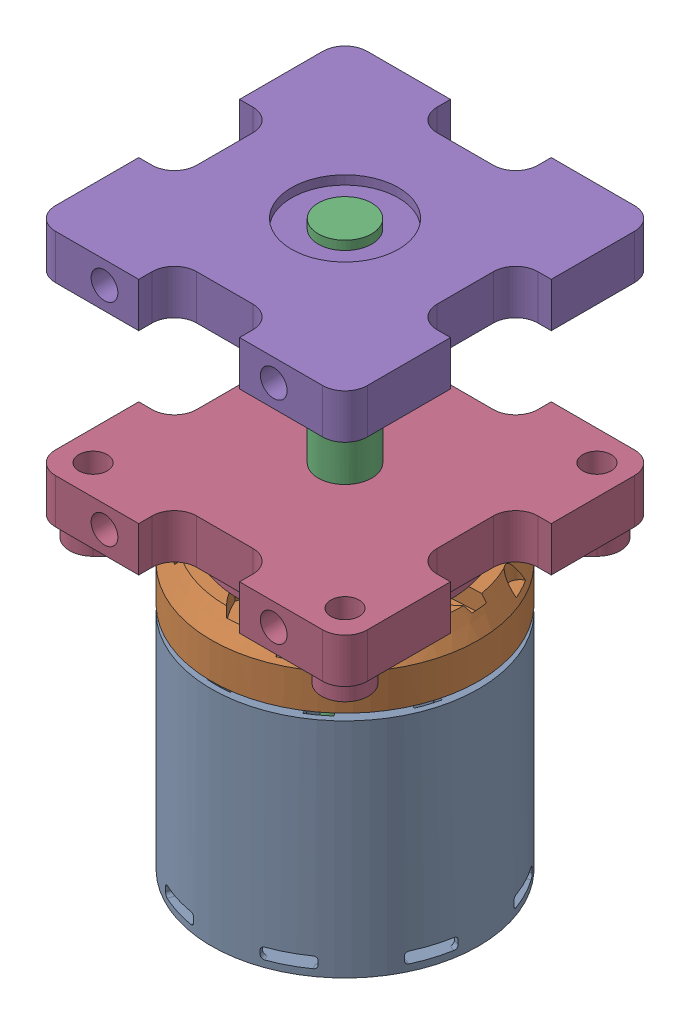
SolidWorks assembly H850 , configuration Default. Lengths in mm.
Overall size (75.22 136.5 75.22).
4 component instances, 4 part files, 7 mates.
Components (placement in the parent):
- body-1: body [Default] at (7.5915 -11.8634 45.6906) x (0.954051 0 0.299644) z (-0.299644 0 0.954051) size (60 50 60)
- top cover-1: top cover [Default] at (7.5915 42.6366 45.6906) x (-0.272077 0 0.962275) z (-0.962275 0 -0.272077) size (60 13.3 60)
- shaft for gearbox-1: shaft for gearbox [Default] at (7.3632 83.6366 39.6949) x (0 -1 0) z (-0.999276 0 0.038053) size (136.5 12 12)
- H850 MOUNT-1: H850 MOUNT [Default] at (7.5915 104.6366 45.6906) x (1 0 0) z (0 1 0) size (70 70 62)
Mates (geometry in assembly coordinates):
- Concentric1: concentric aligned: cylinder of top cover-1 through (7.5915 42.6366 45.6906) axis (0 1 0) radius 3; cylinder of shaft for gearbox-1 through (7.5915 -21.8634 45.6906) axis (0 1 0) radius 4
- Distance2: distance = 10 mm aligned: plane of body-1 through (7.5915 -11.8634 45.6906) normal (0 -1 0); plane of shaft for gearbox-1 through (7.5915 -21.8634 45.6906) normal (0 -1 0)
- Concentric2: concentric anti-aligned: cylinder of body-1 through (7.5915 58.1366 45.6906) axis (0 -1 0) radius 4; cylinder of shaft for gearbox-1 through (7.5915 -21.8634 45.6906) axis (0 1 0) radius 4
- Coincident2: coincident anti-aligned: plane of top cover-1 through (7.5915 52.6366 45.6906) normal (0 1 0); plane of shaft for gearbox-1 through (7.8198 52.6366 51.6862) normal (0 -1 0)
- Concentric3: concentric anti-aligned: cylinder of shaft for gearbox-1 through (7.5915 -21.8634 45.6906) axis (0 1 0) radius 6; cylinder of H850 MOUNT-1 through (7.5915 67.1366 45.6906) axis (0 -1 0) radius 6
- Coincident3: coincident anti-aligned: plane of top cover-1 through (7.5915 52.6366 45.6906) normal (0 1 0); plane of H850 MOUNT-1 through (35.8794 52.6366 17.4026) normal (0 -1 0)
- Parallel1: parallel anti-aligned: plane of H850 MOUNT-1 through (18.9003 114.6366 10.6906) normal (0 0 -1)
